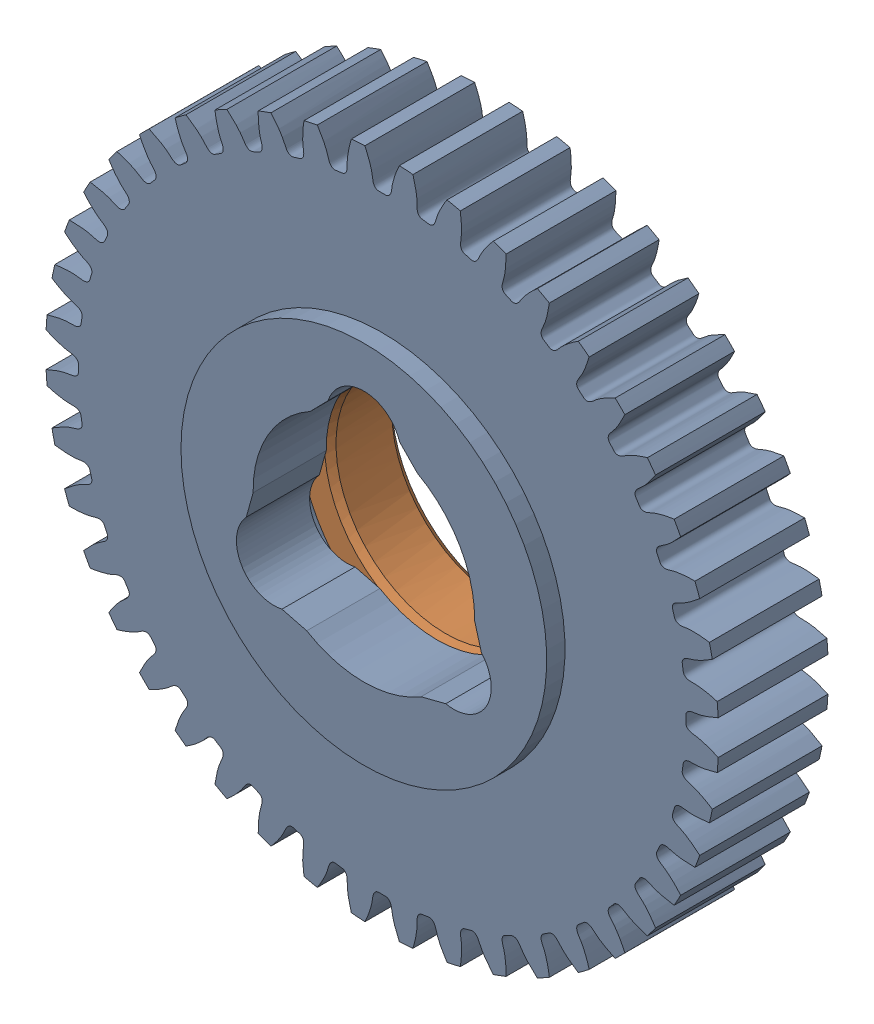
SolidWorks assembly 217-2709-101 Rev1, configuration Default. Lengths in mm.
Overall size (58.74 58.74 12.7).
2 component instances, 2 part files, 0 mates.
Components (placement in the parent):
- 217-2709-001_44t Steel-1: 217-2709-001_44t Steel [Default] at (0 0 3.302) size (58.74 58.74 11.11)
- 217-2428-022 Rev1-1: 217-2428-022 Rev1 [Default] at origin size (28.57 28.57 6.1)
